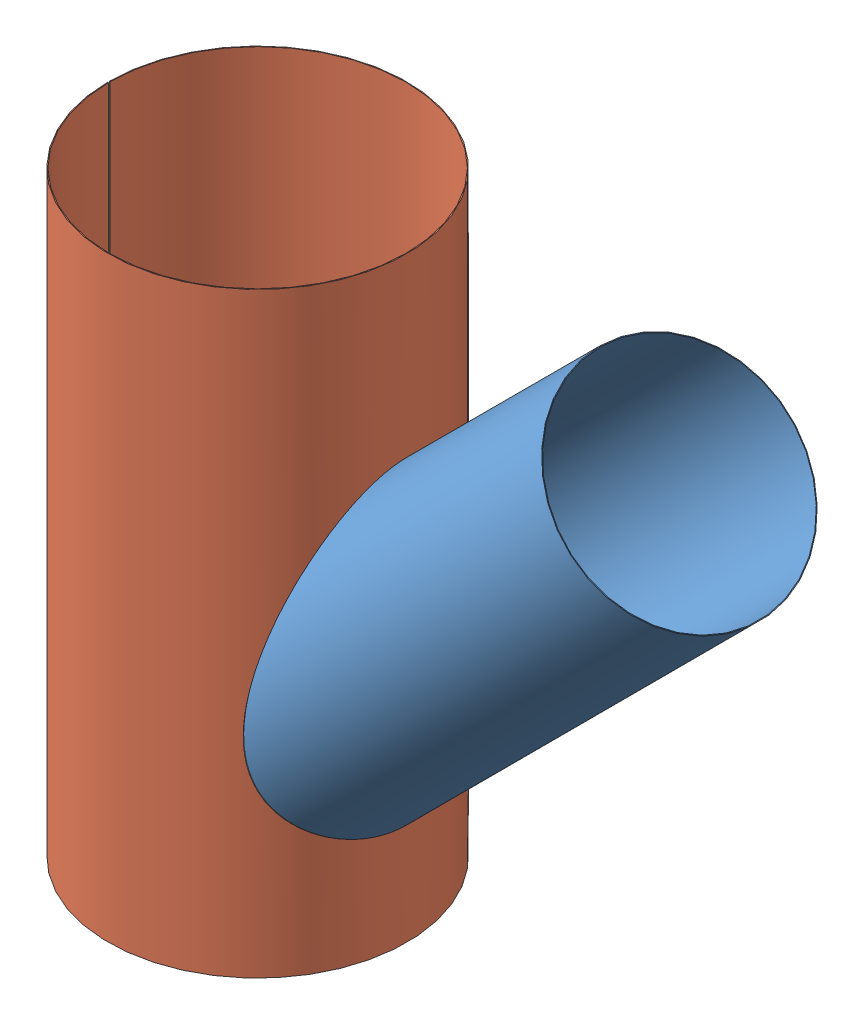
SolidWorks assembly Ensamblaje2.1, configuration Predeterminado. Lengths in mm.
Overall size (872.46 822.46 400).
2 component instances, 2 part files, 7 mates.
Components (placement in the parent):
- CHAPA METALICA4-1: CHAPA METALICA4 [Predeterminado] at origin size (872.46 822.46 400)
- CHAPAMETALICA 3-1: CHAPAMETALICA 3 [Predeterminado] at origin size (400 800 400)
Mates (geometry in assembly coordinates):
- Coincidente1: coordinate: point of ?
- Coincidente3: coincident aligned: line of CHAPA METALICA4-1 through (0 150 0) axis (0.707107 0.707107 0); line of CHAPAMETALICA 3-1 through (0 150 0) axis (0.707107 0.707107 0)
- Coincidente4: coincident: point of CHAPA METALICA4-1; point of CHAPAMETALICA 3-1
- Paralelo1: parallel: plane of ? through (0 0 0) normal (0 0 1)
- Coincidente7: coincident: plane of ? through (0 0 0) normal (0 0 1)
- Coincidente8: coincident: plane of ? through (0 0 0) normal (0 0 1)
- Coincidente9: coincident aligned: plane of ? through (0 0 0) normal (0 0 1)
